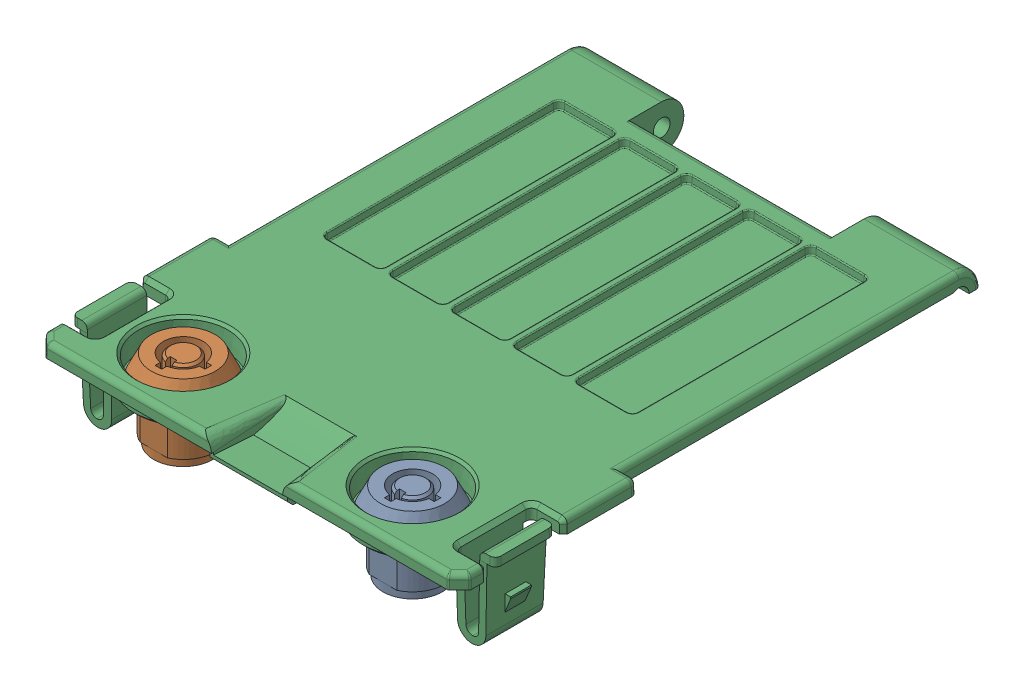
SolidWorks assembly ASY-M-111326 Lid, Cashbox Assy-1, configuration Default. Lengths in mm.
Overall size (76.59 15.65 97.24).
7 component instances, 2 part files, 0 mates.
Components (placement in the parent):
- Lock Assy(Default)-2-1: Lock Assy(Default)-2 [Default] at (19.2 81.5 11.8443) x (0 0 1) z (0 1 0) size (15 15 15.5)
  - Lock - 10220022001-2-1: Lock - 10220022001-2 [Default] at (0 0 7.5) x (-1 0 0) z (0 0 -1) size (15 15 15.5)
    - Lock Body - 10220022001-2-1: Lock Body - 10220022001-2 [Default] x (-1 0 0) z (0 0 1) size (15 15 15.5)
- Lock Assy(Default)-1-2-1: Lock Assy(Default)-1-2 [Default] at (-22.2 81.5 11.8443) x (0 0 1) z (0 1 0) size (15 15 15.5)
  - Lock - 10220022001-1-2-1: Lock - 10220022001-1-2 [Default] at (0 0 7.5) x (-1 0 0) z (0 0 -1) size (15 15 15.5)
    - Lock Body - 10220022001-2-1: Lock Body - 10220022001-2 [Default] x (-1 0 0) z (0 0 1) size (15 15 15.5)
- ASY-M-601303 R6.2 Lid, CashBox-2-1: ASY-M-601303 R6.2 Lid, CashBox-2 [Default] at origin size (76.59 15.65 97.24)
